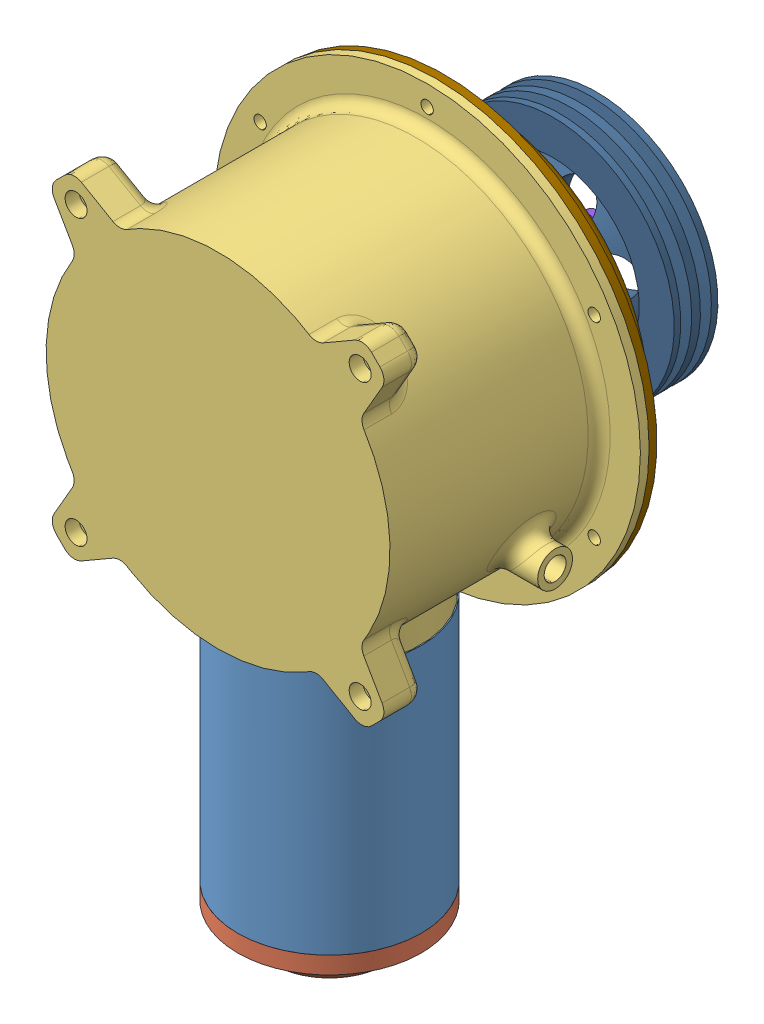
SolidWorks assembly Assem1final, configuration Default. Lengths in mm.
Overall size (421.55 559.71 277.85).
11 component instances, 11 part files, 27 mates.
Components (placement in the parent):
- Bushing-1: Bushing [Default] at (-11.5464 311.6488 165.3206) size (133.35 200.65 133.35)
- Cover of Bushing-1: Cover of Bushing [Default] at (-11.5464 311.9028 165.3206) size (133.35 37.85 133.35)
- Part1,2-1: Part1,2 [Default] at (69.7336 302.8437 87.9706) x (1 0 0) z (0 -1 0) size (310 158.35 310)
- Piston-1: Piston [Default] at (69.7336 38.1817 165.3206) x (0 0 -1) z (1 0 0) size (83.06 78.47 82.55)
- part2a-1: part2a [Default] at (80.9817 244.8759 165.3206) x (-0.998523 0.054339 0) z (0 0 1) size (76.2 220.34 22.13)
- Pin-1: Pin [Default] at (69.7336 38.1817 200.2456) x (0 0 -1) z (-1 0 0) size (69.85 19.05 19.05)
- Clamp - Connecting Rod-1: Clamp - Connecting Rod [Default] at (80.9817 244.8759 165.3206) x (0.998523 -0.054339 0) z (0 0 -1) size (76.2 31.75 20.83)
- Camshaft-1: Camshaft [Default] at (69.7336 302.8437 165.3206) x (0 0 -1) z (0.981689 0.190488 0) size (266.7 128.9 69.85)
- Cover Base Pump-1: Cover Base Pump [Default] at (69.7336 302.8438 246.7206) x (0 0 -1) z (0.866025 -0.5 0) size (82.8 308.6 308.6)
- Wheel-1: Wheel [Default] at (69.7336 302.8437 12.9206) x (0 0 -1) z (0.981689 0.190488 0) size (41.91 176.04 176.04)
- Bolt-1: Bolt [Default] at (69.7336 302.8437 0.2206) x (0.866025 -0.5 0) z (0 0 -1) size (47.71 38.1 22.86)
Mates (geometry in assembly coordinates):
- Coincident1: coincident anti-aligned: plane of Bushing-1 through (69.7336 -8.2464 165.3206) normal (0 -1 0); plane of Cover of Bushing-1 through (69.7336 -8.2464 165.3206) normal (0 1 0)
- Concentric1: concentric aligned: cylinder of Bushing-1 through (130.0586 -8.2464 165.3206) axis (0 1 0) radius 3.175; cylinder of Cover of Bushing-1 through (130.0586 -20.6924 165.3206) axis (0 1 0) radius 3.175
- Concentric2: concentric aligned: cylinder of Bushing-1 through (17.4906 -8.2464 195.4831) axis (0 1 0) radius 3.175; cylinder of Cover of Bushing-1 through (17.4906 -20.6924 195.4831) axis (0 1 0) radius 3.175
- Concentric3: concentric aligned: cylinder of Bushing-1 through (69.7336 192.4017 165.3206) axis (0 -1 0) radius 41.275; cylinder of Piston-1 through (69.7336 3.4155 165.3206) axis (0 -1 0) radius 41.275
- LimitDistance1: limit distance = 2.3753 mm anti-aligned: plane of Piston-1 through (69.7336 -9.046 124.0456) normal (0 -1 0); plane of Cover of Bushing-1 through (69.7336 -11.4214 165.3206) normal (0 1 0)
- Concentric4: concentric aligned: cylinder of Piston-1 through (69.7336 38.1817 292.3206) axis (0 0 -1) radius 9.525; cylinder of part2a-1 through (69.7336 38.1817 171.7356) axis (0 0 -1) radius 9.525
- Width1: width anti-aligned: plane of Piston-1 through (69.7336 38.1817 174.8456) normal (0 0 -1); plane of Piston-1 through (69.7336 38.1817 155.7956) normal (0 0 1); plane of part2a-1 through (69.7336 38.1817 174.2106) normal (0 0 1); plane of part2a-1 through (69.7336 38.1817 156.4306) normal (0 0 -1)
- Concentric5: concentric aligned: cylinder of Piston-1 through (69.7336 38.1817 292.3206) axis (0 0 -1) radius 9.525; cylinder of Pin-1 through (69.7336 38.1817 200.2456) axis (0 0 -1) radius 9.525
- Width2: width aligned: plane of Pin-1 through (69.7336 38.1817 130.3956) normal (0 0 -1); plane of Pin-1 through (69.7336 38.1817 200.2456) normal (0 0 1); plane of part2a-1 through (80.9817 244.8759 158.9056) normal (0 0 -1); plane of part2a-1 through (80.9817 244.8759 171.7356) normal (0 0 1)
- Width3: width aligned: plane of Camshaft-1 through (80.9817 244.8759 178.0206) normal (0 0 -1); plane of Camshaft-1 through (80.9817 244.8759 152.6206) normal (0 0 1); plane of part2a-1 through (80.9817 244.8759 154.9056) normal (0 0 -1); plane of part2a-1 through (80.9817 244.8759 175.7356) normal (0 0 1)
- Concentric6: concentric anti-aligned: cylinder of part2a-1 through (80.9817 244.8759 171.7356) axis (0 0 -1) radius 25.4; cylinder of Camshaft-1 through (80.9817 244.8759 152.6206) axis (0 0 1) radius 25.4
- Concentric8: concentric anti-aligned: cylinder of part2a-1 through (46.8334 201.6677 165.3206) axis (0.054339 0.998523 0) radius 4; cylinder of Clamp - Connecting Rod-1 through (50.5139 269.3006 165.3206) axis (-0.054339 -0.998523 0) radius 3.937
- Width4: width anti-aligned: plane of Camshaft-1 through (80.9817 244.8759 152.6206) normal (0 0 1); plane of Camshaft-1 through (80.9817 244.8759 178.0206) normal (0 0 -1); plane of Clamp - Connecting Rod-1 through (80.9817 244.8759 154.9066) normal (0 0 -1); plane of Clamp - Connecting Rod-1 through (80.9817 244.8759 175.7346) normal (0 0 1)
- Concentric9: concentric aligned: cylinder of Clamp - Connecting Rod-1 through (80.9817 244.8759 178.8588) axis (0 0 1) radius 25.4; cylinder of Camshaft-1 through (80.9817 244.8759 152.6206) axis (0 0 1) radius 25.4
- Concentric15: concentric aligned: cylinder of Camshaft-1 through (69.7336 302.8437 12.9206) axis (0 0 -1) radius 12.7; cylinder of Wheel-1 through (69.7336 302.8437 12.9206) axis (0 0 -1) radius 12.7
- Concentric17: concentric anti-aligned: cylinder of Camshaft-1 through (69.7336 302.8437 12.9206) axis (0 0 -1) radius 12.7; cylinder of Bolt-1 through (69.7336 302.8437 -22.6394) axis (0 0 1) radius 12.7
- Parallel4: parallel aligned: plane of Bushing-1 through (-11.5464 311.6488 165.3206) normal (1 0 0); plane of Bolt-1 through (88.7836 313.8423 -22.6394) normal (1 0 0)
- Perpendicular2: perpendicular: plane of Bushing-1 through (-11.5464 311.6488 165.3206) normal (1 0 0); plane of Pin-1 through (69.7336 38.1817 200.2456) normal (0 -1 0)
- Coincident21: coincident anti-aligned: plane of Camshaft-1 through (62.1788 288.4409 9.1106) normal (-0.981689 -0.190488 0); plane of Wheel-1 through (62.1788 288.4409 12.9206) normal (0.981689 0.190488 0)
- Coincident22: coincident anti-aligned: plane of Camshaft-1 through (69.7336 302.8437 12.9206) normal (0 0 -1); plane of Wheel-1 through (69.7336 302.8437 12.9206) normal (0 0 1)
- Coincident23: coincident anti-aligned: plane of Wheel-1 through (65.4745 324.7929 0.2206) normal (0 0 -1); plane of Bolt-1 through (50.6836 313.8423 0.2206) normal (0 0 1)
- Concentric18: concentric aligned: cylinder of Part1,2-1 through (69.7336 302.8437 359.6247) axis (0 0 1) radius 25.4; cylinder of Camshaft-1 through (69.7336 302.8437 200.2456) axis (0 0 1) radius 25.4
- Concentric21: concentric aligned: cylinder of Part1,2-1 through (69.7336 457.8447 165.3206) axis (0 -1 0) radius 54; cone of Piston-1 through (69.7336 63.5817 165.3206) axis (0 -1 0)
- Coincident27: coincident anti-aligned: plane of Bushing-1 through (69.7336 172.8437 165.3206) normal (0 1 0); plane of Part1,2-1 through (109.8836 172.8437 97.6326) normal (0 -1 0)
- Concentric22: concentric anti-aligned: cylinder of Part1,2-1 through (69.7336 443.0457 97.9706) axis (0 0 -1) radius 4.5; cylinder of Cover Base Pump-1 through (69.7336 443.0458 81.6206) axis (0 0 1) radius 4.445
- Concentric23: concentric anti-aligned: cylinder of Part1,2-1 through (69.7336 162.6417 97.9706) axis (0 0 -1) radius 4.5; circle of Cover Base Pump-1
- Coincident28: coincident anti-aligned: plane of Part1,2-1 through (185.7336 302.8437 87.9706) normal (0 0 -1); plane of Cover Base Pump-1 through (127.8331 403.4751 87.9706) normal (0 0 1)
